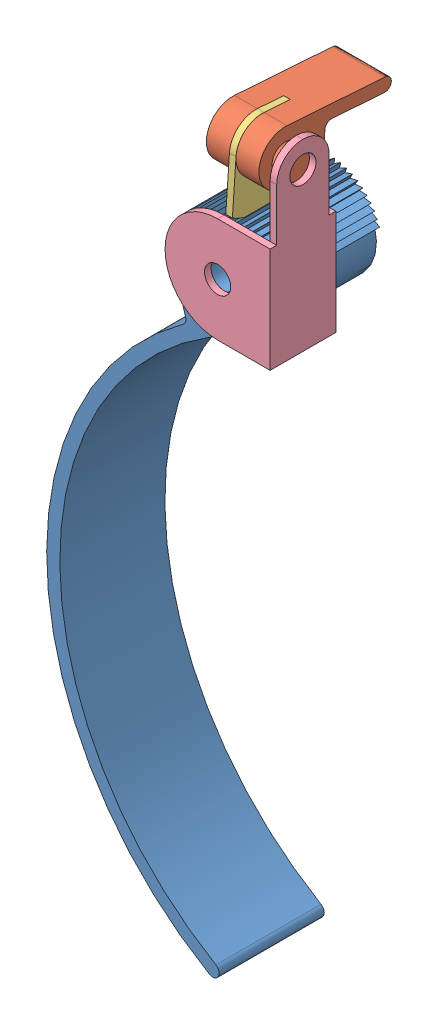
SolidWorks assembly Compact Leg Piece, configuration Default. Lengths in mm.
Overall size (119.45 186.86 34.14).
4 component instances, 4 part files, 5 mates.
Components (placement in the parent):
- Ratchet Clamp-3: Ratchet Clamp [Default] at (-35.7218 -5.7505 64.2938) x (0.280338 -0.959901 0) z (0 0 -1) size (154.32 79.38 25.4)
- Pull Tab Front-1: Pull Tab Front [Default] at (-27.7437 19.6954 57.5203) x (0 0.069803 0.997561) z (-1 0 0) size (31.75 12.7 12.7)
- Ratchet Tab-1: Ratchet Tab [Default] at (-34.8874 19.6954 57.5203) x (0 -0.069803 -0.997561) z (1 0 0) size (12.7 20.32 1.59)
- Merged Plate-1: Merged Plate [Default] at (-23.0218 -5.7505 57.9438) x (0 0 1) z (-1 0 0) size (15.88 44.45 25.4)
Mates (geometry in assembly coordinates):
- Concentric5: concentric: Ratchet Tab-1, Pull Tab Front-1
- Coincident7: coincident: Pull Tab Front-1, Ratchet Tab-1
- Coincident11: coincident: Pull Tab Front-1, Ratchet Tab-1
- Coincident16: coincident: Ratchet Clamp-3, Merged Plate-1
- Concentric9: concentric: Ratchet Clamp-3, Merged Plate-1
